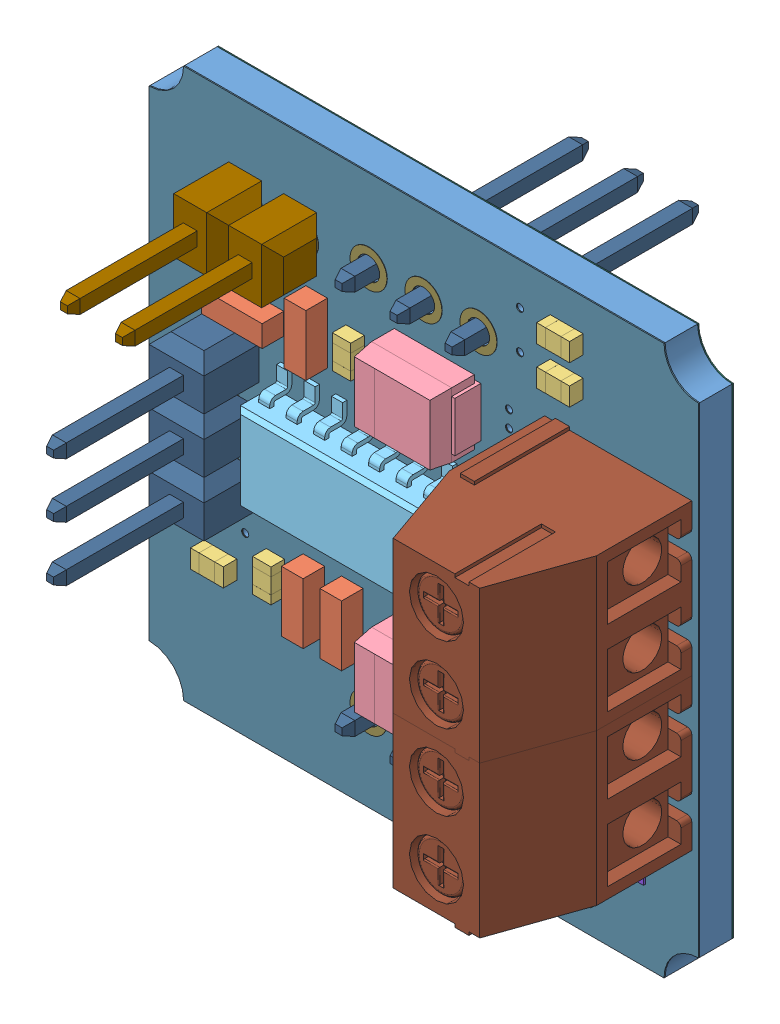
SolidWorks assembly TROYKA_AMPLIFIER_D, configuration Default. Lengths in mm.
Overall size (25.4 25.4 18.38).
40 component instances, 16 part files, 0 mates.
Components (placement in the parent):
- TROYKA_AMPLIFIER_D_Board-1: TROYKA_AMPLIFIER_D_Board [По умолчанию] at origin size (25.4 25.4 1.5)
- TROYKA_AMPLIFIER_D__Packages-1: TROYKA_AMPLIFIER_D__Packages [По умолчанию] at origin size (22.55 22.57 18.38)
  - TROYKA_AMPLIFIER_D_C0603-1: TROYKA_AMPLIFIER_D_C0603 [По умолчанию] at (7.62 7.239 1.5525) x (0 1 0) z (0 0 1) size (2.8 1 1)
  - TROYKA_AMPLIFIER_D_C0603-2: TROYKA_AMPLIFIER_D_C0603 [По умолчанию] at (7.747 18.034 1.5525) x (0 -1 0) z (0 0 1) size (2.8 1 1)
  - TROYKA_AMPLIFIER_D_C0603-3: TROYKA_AMPLIFIER_D_C0603 [По умолчанию] at (9.398 7.239 1.5525) x (0 1 0) z (0 0 1) size (2.8 1 1)
  - TROYKA_AMPLIFIER_D_C0603-4: TROYKA_AMPLIFIER_D_C0603 [По умолчанию] at (4.826 17.399 1.5525) x (-1 0 0) z (0 0 1) size (2.8 1 1)
  - TROYKA_AMPLIFIER_D_R0603-1: TROYKA_AMPLIFIER_D_R0603 [По умолчанию] at (5.842 7.239 1.5525) x (0 -1 0) z (0 0 1) size (1.52 0.86 0.64)
  - TROYKA_AMPLIFIER_D_R0603-2: TROYKA_AMPLIFIER_D_R0603 [По умолчанию] at (3.302 6.477 1.5525) size (1.52 0.86 0.64)
  - TROYKA_AMPLIFIER_D_R0603-3: TROYKA_AMPLIFIER_D_R0603 [По умолчанию] at (9.525 18.034 1.5525) x (0 -1 0) z (0 0 1) size (1.52 0.86 0.64)
  - TROYKA_AMPLIFIER_D_R0603-4: TROYKA_AMPLIFIER_D_R0603 [По умолчанию] at (4.826 19.177 1.5525) size (1.52 0.86 0.64)
  - TROYKA_AMPLIFIER_D_R0603-5: TROYKA_AMPLIFIER_D_R0603 [По умолчанию] at (19.304 23.495 1.5525) size (1.52 0.86 0.64)
  - TROYKA_AMPLIFIER_D_R0603-6: TROYKA_AMPLIFIER_D_R0603 [По умолчанию] at (19.304 21.717 1.5525) size (1.52 0.86 0.64)
  - TROYKA_AMPLIFIER_D_SMC_B-1: TROYKA_AMPLIFIER_D_SMC_B [По умолчанию] at (13.335 6.985 1.5525) size (4 3 2.12)
  - TROYKA_AMPLIFIER_D_SMC_B-2: TROYKA_AMPLIFIER_D_SMC_B [По умолчанию] at (13.335 18.415 1.5525) size (4 3 2.12)
  - TROYKA_AMPLIFIER_D_SO16_SHORTPADS-1: TROYKA_AMPLIFIER_D_SO16_SHORTPADS [По умолчанию] at (10.795 12.7 1.5525) x (-1 0 0) z (0 0 1) size (10 6.2 1.75)
  - TROYKA_AMPLIFIER_D_J0402-1: TROYKA_AMPLIFIER_D_J0402 [По умолчанию] at (13.335 23.876 -0.0525) x (1 0 0) z (0 0 -1) size (2 1.2 0.1)
  - TROYKA_AMPLIFIER_D_J0402-2: TROYKA_AMPLIFIER_D_J0402 [По умолчанию] at (10.795 24.511 -0.0525) x (1 0 0) z (0 0 -1) size (2 1.2 0.1)
  - TROYKA_AMPLIFIER_D__INDC4509X190N-1: TROYKA_AMPLIFIER_D__INDC4509X190N [По умолчанию] at (20.066 3.81 1.5525) x (-1 0 0) z (0 0 1) size (5.76 1.6 1.9)
    - TROYKA_AMPLIFIER_D__BLM41PG102SZ1B v1-1: TROYKA_AMPLIFIER_D__BLM41PG102SZ1B v1 [По умолчанию] at origin size (5.76 1.6 1.9)
      - TROYKA_AMPLIFIER_D_Body-1: TROYKA_AMPLIFIER_D_Body [По умолчанию] at (0 0 0.1) size (4.5 1.6 1.8)
      - TROYKA_AMPLIFIER_D_Pins-1: TROYKA_AMPLIFIER_D_Pins [По умолчанию] at origin size (5.76 0.96 0.1)
  - TROYKA_AMPLIFIER_D__PIN_1X2-1: TROYKA_AMPLIFIER_D__PIN_1X2 [По умолчанию] at (5.715 21.336 1.5525) x (-1 0 0) z (0 0 1) size (5.08 2.54 11.38)
    - TROYKA_AMPLIFIER_D_Model-1: TROYKA_AMPLIFIER_D_Model [По умолчанию] at (-1.27 0 0) size (5.08 2.54 11.38)
  - TROYKA_AMPLIFIER_D__PIN_1X3-1: TROYKA_AMPLIFIER_D__PIN_1X3 [По умолчанию] at (12.7 21.59 -0.0525) x (1 0 0) z (0 0 -1) size (7.62 2.54 11.38)
    - TROYKA_AMPLIFIER_D_Model (1)-1: TROYKA_AMPLIFIER_D_Model (1) [По умолчанию] at (-2.54 0 0) size (7.62 2.54 11.38)
  - TROYKA_AMPLIFIER_D__PIN_1X3-1-1: TROYKA_AMPLIFIER_D__PIN_1X3-1 [По умолчанию] at (3.81 12.7 1.5525) x (0 1 0) z (0 0 1) size (7.62 2.54 11.38)
    - TROYKA_AMPLIFIER_D_Model (1)-1: TROYKA_AMPLIFIER_D_Model (1) [По умолчанию] at (-2.54 0 0) size (7.62 2.54 11.38)
  - TROYKA_AMPLIFIER_D__PIN_1X3-2-1: TROYKA_AMPLIFIER_D__PIN_1X3-2 [По умолчанию] at (12.7 3.81 -0.0525) x (-1 0 0) z (0 0 -1) size (7.62 2.54 11.38)
    - TROYKA_AMPLIFIER_D_Model (1)-1: TROYKA_AMPLIFIER_D_Model (1) [По умолчанию] at (-2.54 0 0) size (7.62 2.54 11.38)
  - TROYKA_AMPLIFIER_D__SCREWTERMINAL-3.5MM-4-1: TROYKA_AMPLIFIER_D__SCREWTERMINAL-3.5MM-4 [По умолчанию] at (21.6852 7.493 1.5525) x (0 1 0) z (0 0 1) size (14.3 6.8 10.4)
    - TROYKA_AMPLIFIER_D__SCREWTERMINAL-3.5MM-2 v1 v1-1: TROYKA_AMPLIFIER_D__SCREWTERMINAL-3.5MM-2 v1 v1 [По умолчанию] at origin size (7.3 6.8 10.4)
      - TROYKA_AMPLIFIER_D_14420348.f3d -1: TROYKA_AMPLIFIER_D_14420348.f3d  [По умолчанию] at (1.75 0 0) x (1 0 0) z (0 -1 0) size (7.3 10.4 6.8)
    - TROYKA_AMPLIFIER_D__SCREWTERMINAL-3.5MM-2 v1 v1-2: TROYKA_AMPLIFIER_D__SCREWTERMINAL-3.5MM-2 v1 v1 [По умолчанию] at (7 0 0) size (7.3 6.8 10.4)
      - TROYKA_AMPLIFIER_D_14420348.f3d -1: TROYKA_AMPLIFIER_D_14420348.f3d  [По умолчанию] at (1.75 0 0) x (1 0 0) z (0 -1 0) size (7.3 10.4 6.8)
  - TROYKA_AMPLIFIER_D__SDR0302-1: TROYKA_AMPLIFIER_D__SDR0302 [По умолчанию] at (5.715 3.175 1.5525)
    - TROYKA_AMPLIFIER_D_SDR0302-102KL v1-1: TROYKA_AMPLIFIER_D_SDR0302-102KL v1 [По умолчанию] at (0.006 0.0014 2.5044) x (1 0 0) z (0 1 0)
- TROYKA_AMPLIFIER_D_1-copper-1: TROYKA_AMPLIFIER_D_1-copper [По умолчанию] at (0 0 1.5) size (24.59 24.59 0.08)
- TROYKA_AMPLIFIER_D_16-copper-1: TROYKA_AMPLIFIER_D_16-copper [По умолчанию] at (0 0 -0.035) size (24.59 24.64 0.08)
- TROYKA_AMPLIFIER_D_1-soldermask_1-1: TROYKA_AMPLIFIER_D_1-soldermask_1 [По умолчанию] at (0 0 1.5) size (25.4 25.4 0.05)
- TROYKA_AMPLIFIER_D_16-soldermask_1-1: TROYKA_AMPLIFIER_D_16-soldermask_1 [По умолчанию] at origin size (25.4 25.4 0.05)
